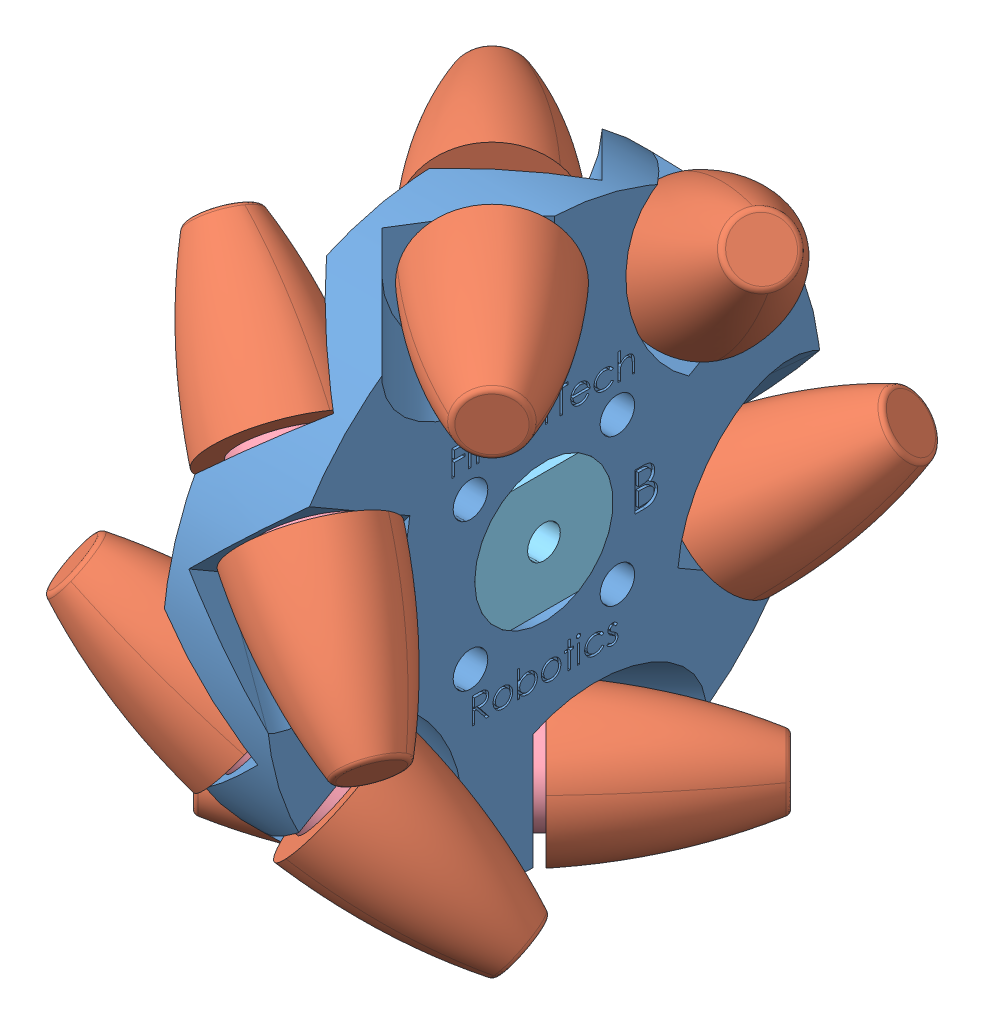
SolidWorks assembly Mecanum Wheel B, configuration Valor predeterminado. Lengths in mm.
Overall size (40.55 59.83 66.05).
32 component instances, 5 part files, 0 mates.
Components (placement in the parent):
- Mecanum Hub Mirrored B R2-1: Mecanum Hub Mirrored B R2 [Valor predeterminado] at (-14.8574 0.4229 7.5528) size (9.53 50.8 50.8)
- rubber roller-1: rubber roller [Valor predeterminado] at (-17.3237 21.0604 5.0865) x (-0.707107 0 -0.707107) z (0.499904 -0.707242 -0.499904) size (15.88 13.22 13.13)
- rubber roller-2: rubber roller [Valor predeterminado] at (-17.3231 12.877 24.1925) x (-0.707107 0.612372 -0.353553) z (0.253872 -0.246803 -0.93522) size (15.88 13.22 13.13)
- rubber roller-3: rubber roller [Valor predeterminado] at (-17.3231 -7.7605 26.6582) x (-0.707107 0.612372 0.353553) z (-0.391226 -0.75531 0.525784) size (15.88 13.22 13.13)
- rubber roller-4: rubber roller [Valor predeterminado] at (-17.3231 -20.2146 10.0185) x (-0.707107 0 0.707107) z (0.562502 0.605957 0.562502) size (15.88 13.22 13.13)
- rubber roller-5: rubber roller [Valor predeterminado] at (-17.3231 8.6063 -11.5527) x (-0.707107 -0.612372 -0.353553) z (-0.707107 0.61243 0.353453) size (15.88 13.22 13.13)
- rubber roller-6: rubber roller [Valor predeterminado] at (-17.3231 -12.0312 -9.087) x (-0.707107 -0.612372 0.353553) z (-0.5772 0.788695 0.211661) size (15.88 13.22 13.13)
- rubber roller-7: rubber roller [Valor predeterminado] at (-12.3912 -12.0317 24.1922) x (0.707107 -0.612372 -0.353553) z (-0.685872 -0.715596 -0.132296) size (15.88 13.22 13.13)
- rubber roller-8: rubber roller [Valor predeterminado] at (-12.3912 -20.2146 5.0865) x (0.707107 0 -0.707107) z (-0.253824 0.933352 -0.253824) size (15.88 13.22 13.13)
- rubber roller-9: rubber roller [Valor predeterminado] at (-12.3912 -7.76 -11.553) x (0.707107 0.612372 -0.353553) z (-0.001796 -0.498443 -0.866921) size (15.88 13.22 13.13)
- rubber roller-10: rubber roller [Valor predeterminado] at (-12.3912 8.6058 26.6585) x (0.707107 -0.612372 0.353553) z (0.069934 0.558113 0.826813) size (15.88 13.22 13.13)
- rubber roller-11: rubber roller [Valor predeterminado] at (-12.3912 12.8775 -9.0867) x (0.707107 0.612372 0.353553) z (-0.460574 0.01948 0.887408) size (15.88 13.22 13.13)
- rubber roller-12: rubber roller [Valor predeterminado] at (-12.3912 21.0604 10.019) x (0.707107 0 0.707107) z (-0.138038 -0.98076 0.138038) size (15.88 13.22 13.13)
- steel pin-1: steel pin [Valor predeterminado] at (-5.6406 21.0604 16.7696) x (-0.707107 0 -0.707107) z (-0.548656 0.630836 0.548656) size (32.38 3.18 3.18)
- steel pin-2: steel pin [Valor predeterminado] at (-3.4109 0.8287 31.1486) x (-0.707107 0.612372 -0.353553) z (-0.30884 -0.717251 -0.624635) size (32.38 3.18 3.18)
- steel pin-3: steel pin [Valor predeterminado] at (-3.4109 -19.8088 19.7021) x (-0.707107 0.612372 0.353553) z (0.672023 0.737529 0.066609) size (32.38 3.18 3.18)
- steel pin-4: steel pin [Valor predeterminado] at (-3.4109 -20.2146 -3.8938) x (-0.707107 0 0.707107) z (-0.643237 0.415323 -0.643237) size (32.38 3.18 3.18)
- steel pin-5: steel pin [Valor predeterminado] at (-3.4109 0.0171 -16.0431) x (-0.707107 -0.612372 0.353553) z (0.683232 -0.462866 0.564756) size (32.38 3.18 3.18)
- steel pin-6: steel pin [Valor predeterminado] at (-3.4109 20.6546 -4.5966) x (-0.707107 -0.612372 -0.353553) z (-0.635525 0.769593 -0.061923) size (32.38 3.18 3.18)
- Flat Washer Type A Narrow_AI_FW 0.125-1: Flat Washer Type A Narrow_AI_FW 0.125 [Valor predeterminado] at (-12.9659 21.0604 9.4443) x (-0.707107 0 -0.707107) z (0.699565 0.145662 -0.699565) size (0.81 7.92 7.92)
- Flat Washer Type A Narrow_AI_FW 0.125-2: Flat Washer Type A Narrow_AI_FW 0.125 [Valor predeterminado] at (-12.9659 12.3797 -9.3741) x (-0.707107 -0.612372 -0.353553) z (0.353553 -0.739199 0.573223) size (0.81 7.92 7.92)
- Flat Washer Type A Narrow_AI_FW 0.125-3: Flat Washer Type A Narrow_AI_FW 0.125 [Valor predeterminado] at (-12.9659 -8.2578 -11.2656) x (-0.707107 -0.612372 0.353553) z (-0.353553 0.739199 0.573223) size (0.81 7.92 7.92)
- Flat Washer Type A Narrow_AI_FW 0.125-4: Flat Washer Type A Narrow_AI_FW 0.125 [Valor predeterminado] at (-12.9659 -20.2146 5.6612) x (-0.707107 0 0.707107) z (-0.707107 0 -0.707107) size (0.81 7.92 7.92)
- Flat Washer Type A Narrow_AI_FW 0.125-5: Flat Washer Type A Narrow_AI_FW 0.125 [Valor predeterminado] at (-12.9659 -11.5339 24.4796) x (-0.707107 0.612372 0.353553) z (-0.353553 -0.739199 0.573223) size (0.81 7.92 7.92)
- Flat Washer Type A Narrow_AI_FW 0.125-6: Flat Washer Type A Narrow_AI_FW 0.125 [Valor predeterminado] at (-12.9659 9.1036 26.3711) x (-0.707107 0.612372 -0.353553) z (0.353553 0.739199 0.573223) size (0.81 7.92 7.92)
- Flat Washer Type A Narrow_AI_FW 0.125-7: Flat Washer Type A Narrow_AI_FW 0.125 [Valor predeterminado] at (-16.7489 9.1036 -11.2656) x (0.707107 0.612372 0.353553) z (-0.353553 -0.126826 0.926777) size (0.81 7.92 7.92)
- Flat Washer Type A Narrow_AI_FW 0.125-8: Flat Washer Type A Narrow_AI_FW 0.125 [Valor predeterminado] at (-16.7489 21.0604 5.6612) x (0.707107 0 0.707107) z (-0.707107 0 0.707107) size (0.81 7.92 7.92)
- Flat Washer Type A Narrow_AI_FW 0.125-9: Flat Washer Type A Narrow_AI_FW 0.125 [Valor predeterminado] at (-16.7489 12.3797 24.4796) x (0.707107 -0.612372 0.353553) z (-0.353553 0.126826 0.926777) size (0.81 7.92 7.92)
- Flat Washer Type A Narrow_AI_FW 0.125-10: Flat Washer Type A Narrow_AI_FW 0.125 [Valor predeterminado] at (-16.7489 -11.5339 -9.3741) x (0.707107 0.612372 -0.353553) z (0.353553 0.126826 0.926777) size (0.81 7.92 7.92)
- Flat Washer Type A Narrow_AI_FW 0.125-11: Flat Washer Type A Narrow_AI_FW 0.125 [Valor predeterminado] at (-16.7489 -20.2146 9.4443) x (0.707107 0 -0.707107) z (0.707107 0 0.707107) size (0.81 7.92 7.92)
- Flat Washer Type A Narrow_AI_FW 0.125-12: Flat Washer Type A Narrow_AI_FW 0.125 [Valor predeterminado] at (-16.7489 -8.2578 26.3711) x (0.707107 -0.612372 -0.353553) z (0.353553 -0.126826 0.926777) size (0.81 7.92 7.92)
- Mecanum mount R2-1: Mecanum mount R2 [Valor predeterminado] at (-16.4449 0.4229 7.5528) x (-1 0 0) z (0 0 -1) size (9.53 25.4 25.4)
